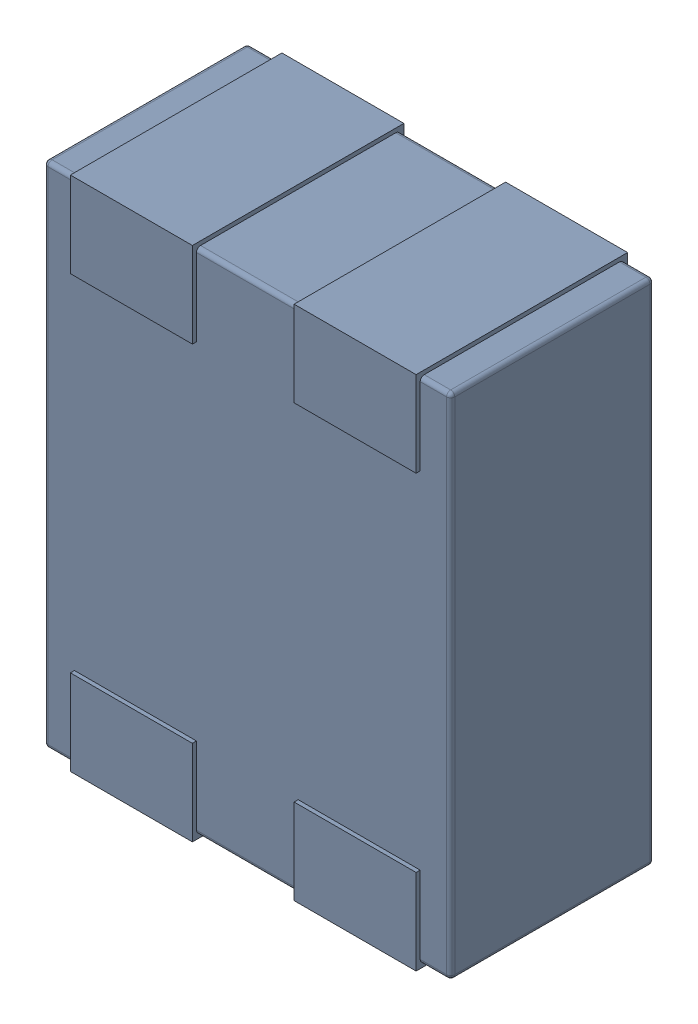
SolidWorks assembly 3D_PCB1_2021-12-30 (1).step, configuration Défaut. Lengths in mm.
Overall size (1 1.27 0.52).
2 component instances, 1 part files, 0 mates.
Components (placement in the parent):
- a3ec64f90eb5404ebd79eca0046a794a.step-1: a3ec64f90eb5404ebd79eca0046a794a.step [Défaut] at (5.0419 -6.8961 1.6) size (1 1.27 0.52)
  - SOLID.step_650-1: SOLID.step_650 [Défaut] at origin size (1 1.27 0.52)
